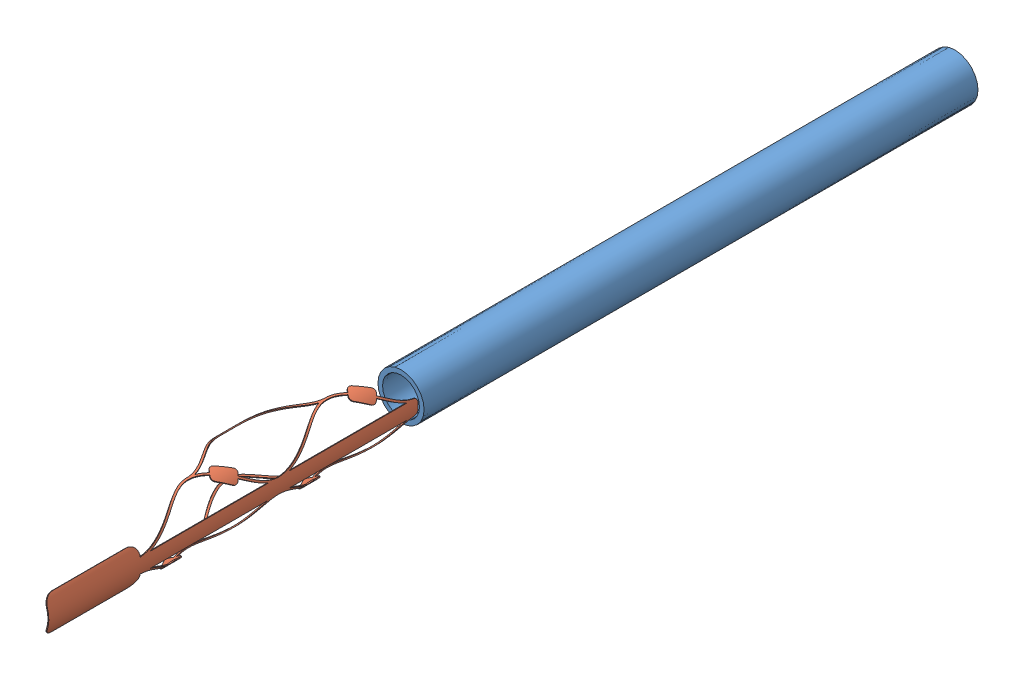
SolidWorks assembly Assem1.1_inverse, configuration Default. Lengths in mm.
Overall size (3.56 3.44 50.13).
2 component instances, 2 part files, 3 mates.
Components (placement in the parent):
- Catheter_inverse-1: Catheter_inverse [Default] at (7.8162 16.1379 9.4845) size (3 3 30)
- undefined_scaffold1.2_inverse-1: undefined_scaffold1.2_inverse [Default] at (8.6912 15.1115 37.148) x (0 0 1) z (1 0 0) size (20.19 3.44 3.03)
Mates (geometry in assembly coordinates):
- Coincident2: coincident: point of Catheter_inverse-1; point of undefined_scaffold1.2_inverse-1
- Parallel1: parallel: line of Catheter_inverse-1 through (8.8162 16.297 39.4845) axis (0 -1 0); line of undefined_scaffold1.2_inverse-1 through (8.7162 15.9224 39.4845) axis (0 1 0)
- Concentric1: concentric anti-aligned: circle of Catheter_inverse-1; circle of undefined_scaffold1.2_inverse-1
